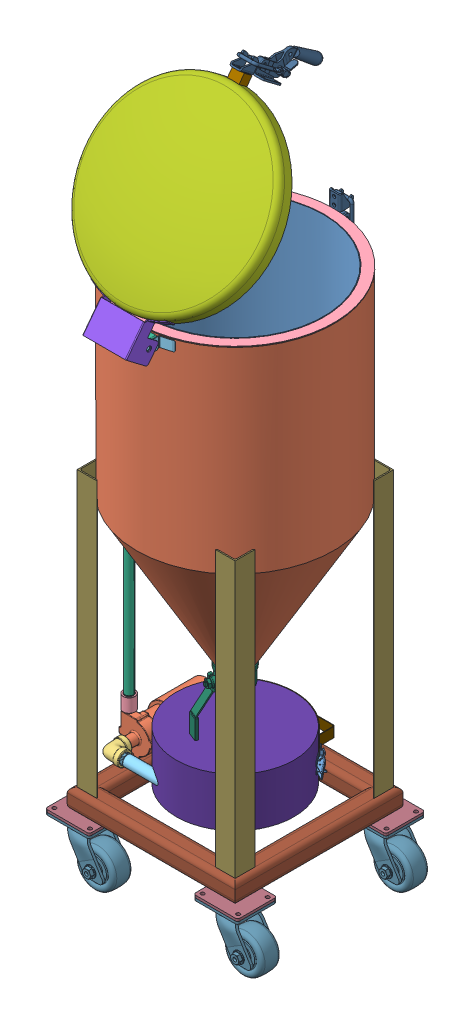
SolidWorks assembly Full Assembly - Working Copy, configuration Default. Lengths in mm.
Overall size (805.82 1990.16 905.72).
42 component instances, 28 part files, 51 mates.
Components (placement in the parent):
- Inner Tank (SUS304 Stainless)-1: Inner Tank (SUS304 Stainless) [Default] at origin size (460.38 809.15 460.38)
- Outer Tank (5052 Aluminum)-1: Outer Tank (5052 Aluminum) [Default] at (0 -53.975 0) size (510.43 880.41 510.43)
- Part2^Full Assembly - Working Copy-1: Part2^Full Assembly - Working Copy [Default] at origin size (510.43 1.27 510.43) (virtual)
- Part1^Full Assembly - Working Copy-1: Part1^Full Assembly - Working Copy [Default] at origin size (511.18 1.59 511.18) (virtual)
- Aluminum Hinge Bottom-1: Aluminum Hinge Bottom [Default] at (0 423.092 293.37) size (172.01 30.25 52.98)
- Aluminum Hinge Top-1: Aluminum Hinge Top [Default] at (0 452.7347 293.37) x (-1 0 0) z (0 0 1) size (104.78 30.94 44.15)
- Lid Assembly-1: Lid Assembly [Default] at (0 671.8933 125.664) x (-1 0 0) z (0 0.79683 -0.604203) size (548.2 438.64 642.51)
  - Lid-2: Lid [Default] at (211.2181 -60.2546 -11.3558) x (0.978448 -0.106422 -0.176957) z (0.118934 -0.410093 0.904256) size (467.18 231.16 437.78)
  - Stainless Hinge (Lid)-1: Stainless Hinge (Lid) [Default] at (0 31.628 -311.3405) x (-1 0 0) z (0 0 -1) size (198.67 69.73 99.8)
  - Part1-1: Part1 [Default] at origin size (30.23 25.4 22.84)
  - 5071A590-1: 5071A590 [Default] at (0.0381 -49.8475 255.0668) x (-1 0 0) z (0 1 0) size (60.86 76.1 227.53)
- 5071A590-1: 5071A590 [Default] at (0 407.035 -255.2141) x (1 0 0) z (0 1 0) size (60.86 76.1 227.53)
- Frame Assembly-1: Frame Assembly [Default] at (0 -711.2 0) x (-1 0 0) z (0 0 1) size (805.82 911.23 805.82)
  - Copy of Base Support^Frame Assembly-1: Copy of Base Support^Frame Assembly [Default<As Machined>] at origin size (434.34 50.8 434.34) (virtual)
  - Copy of Legs^Frame Assembly-1: Copy of Legs^Frame Assembly [Default<As Machined>] at (3.4616 1288.0635 -34.29) x (-0.788011 0 0.615661) z (0.615661 0 0.788011) size (574.08 711.2 574.08) (virtual)
  - Caster Plate-1: Caster Plate [Default] at (191.77 57.15 191.77) x (-1 0 0) z (0 0 1) size (114.3 6.35 101.6)
  - Caster Plate-2: Caster Plate [Default] at (191.77 57.15 -191.77) x (-1 0 0) z (0 0 1) size (114.3 6.35 101.6)
  - Caster Plate-3: Caster Plate [Default] at (-191.77 57.15 191.77) x (-1 0 0) z (0 0 1) size (114.3 6.35 101.6)
  - Caster Plate-4: Caster Plate [Default] at (-191.77 57.15 -191.77) x (-1 0 0) z (0 0 1) size (114.3 6.35 101.6)
  - Caster Wheels-2: Caster Wheels [2531T25] at (-236.22 149.225 191.77) x (1 0 0) z (0 0 -1) size (152.4 142.88 101.6)
  - Caster Wheels-3: Caster Wheels [2531T25] at (147.32 149.225 191.77) x (1 0 0) z (0 0 -1) size (152.4 142.88 101.6)
  - Caster Wheels-4: Caster Wheels [2531T25] at (-236.22 149.225 -191.77) x (1 0 0) z (0 0 -1) size (152.4 142.88 101.6)
  - Caster Wheels-5: Caster Wheels [2531T25] at (147.32 149.225 -191.77) x (1 0 0) z (0 0 -1) size (152.4 142.88 101.6)
- 2in Ball Valve-1: 2in Ball Valve [4286K29] at (0 -463.2428 0) x (-0.932381 0 -0.361477) z (0 1 0) size (85.6 128.78 218.48)
- Threaded Adaper - 2in-1: Threaded Adaper - 2in [Default] at (0 -351.9527 0) x (-0.837169 0 -0.546944) z (-0.546944 0 0.837169) size (63.5 76.2 63.5)
- Filter Assembly-1: Filter Assembly [Default] at (0 -638.0329 0) x (-1 0 0) z (0 0 -1) size (336.71 203.2 333.38)
  - Filter Case-1: Filter Case [Default] at origin size (304.8 127 304.8)
  - Filter Cover Plate-1: Filter Cover Plate [Default] x (-1 0 0) z (0 0 -1) size (208.06 127 68.61)
  - Threaded Adaper - 2in-2: Threaded Adaper - 2in [Default] at (0 63.5 0) size (63.5 76.2 63.5)
  - Filter Screen Latches - 1889A430-1: Filter Screen Latches - 1889A430 [Default] at (116.2139 0 99.0468) x (0 -1 0) z (-0.600065 0 0.799951) size (30 20.98 87.72)
  - Filter Screen Latches - 1889A430-2: Filter Screen Latches - 1889A430 [Default] at (-116.1817 0 98.9703) x (0 1 0) z (0.606538 0 0.795055) size (30 20.98 87.72)
- Chugger Pump-1: Chugger Pump [Default] at (-191.77 -663.956 66.675) size (88.39 112.27 235.08)
- 0.75 NPT Elbow Fitting-1: 0.75 NPT Elbow Fitting [4464K15] at (-191.77 -663.956 126.619) x (0 0 1) z (0 1 0) size (52.8 52.55 37.59)
- 0.5 NPT Coupler - 4452K114-1: 0.5 NPT Coupler - 4452K114 [4452K114] at (-217.17 -597.916 57.15) x (-0.998705 0 0.05088) z (0 1 0) size (30.48 30.48 35.05)
- 0.75 x 8 inch pipe 4548K199-1: 0.75 x 8 inch pipe 4548K199 [4548K199] at (-69.9262 -663.956 126.619) size (203.39 27.53 27.76)
- 0.5 x 18 inch pipe-1: 0.5 x 18 inch pipe [4816K124] at (-217.17 -370.332 57.15) x (0 -1 0) z (0.309099 0 -0.95103) size (458.16 22.05 22.45)
- 0.5 45 Elbow 4452K424-1: 0.5 45 Elbow 4452K424 [4452K424] at (-217.17 -161.5821 57.15) x (0 0 1) z (-1 0 0) size (30.73 48.78 41.55)
- 0.5 x 3 inch pipe-1: 0.5 x 3 inch pipe [4548K175] at (-245.3796 -111.2745 57.15) x (0.707107 -0.707107 0) z (0.690919 0.690919 0.212746) size (76.37 22.35 22.37)
- 0.5 45 Elbow 4452K424-2: 0.5 45 Elbow 4452K424 [4452K424] at (-257.9635 -98.6906 57.15) x (0 0 -1) z (0.707107 0.707107 0) size (30.73 48.78 41.55)
- 0.5 x 18 inch pipe-2: 0.5 x 18 inch pipe [4816K124] at (-273.5891 147.7829 57.15) x (0 -1 0) z (0.915986 0 0.40121) size (458.16 22.05 22.45)
- 0.5 90 Elbow 4452K424-1: 0.5 90 Elbow 4452K424 [4452K414] at (-273.5891 384.9808 57.15) x (-1 0 0) z (0 0 1) size (44.42 44.16 30.73)
- 0.5 x 2 inch pipe-1: 0.5 x 2 inch pipe [4548K173] at (-240.0448 384.9808 57.15) size (50.97 22.35 22.37)
Mates (geometry in assembly coordinates):
- Distance1: distance = 3.175 mm aligned: plane of Inner Tank (SUS304 Stainless)-1 through (0 457.2 0) normal (0 1 0); plane of Outer Tank (5052 Aluminum)-1 through (0 454.025 0) normal (0 1 0)
- Parallel2: parallel anti-aligned: plane of Aluminum Hinge Bottom-1 through (0 423.092 293.37) normal (0 1 0); plane of Aluminum Hinge Top-1 through (0 452.7347 293.37) normal (0 -1 0)
- Coincident3: coincident anti-aligned: plane of Aluminum Hinge Bottom-1 through (0 423.092 293.37) normal (1 0 0); plane of Aluminum Hinge Top-1
- Coincident4: coincident aligned: plane of Aluminum Hinge Bottom-1 through (0 421.8016 293.37) normal (0 0 1); plane of Aluminum Hinge Top-1 through (0 454.025 293.37) normal (0 0 1)
- Coincident5: coincident anti-aligned: plane of Aluminum Hinge Bottom-1 through (0 423.092 293.37) normal (0 1 0); plane of Aluminum Hinge Top-1 through (52.3875 423.092 293.37) normal (0 -1 0)
- Coincident6: coincident aligned: plane of Outer Tank (5052 Aluminum)-1 through (0 454.025 0) normal (0 1 0); plane of Aluminum Hinge Top-1 through (0 454.025 293.37) normal (0 1 0)
- Concentric3: concentric aligned: cylinder of Aluminum Hinge Top-1 through (-52.3908 437.824 279.0825) axis (1 0 0) radius 6.35; cylinder of Lid Assembly-1/Stainless Hinge (Lid)-1 through (-99.3063 437.824 279.0825) axis (1 0 0) radius 6.35
- Width1: width anti-aligned: plane of Lid Assembly-1/Stainless Hinge (Lid)-1 through (56.4832 475.2003 381.5539) normal (1 0 0); plane of Lid Assembly-1/Stainless Hinge (Lid)-1 through (-56.4832 475.2003 381.5539) normal (-1 0 0); plane of Aluminum Hinge Bottom-1 through (-53.975 369.5033 293.37) normal (-1 0 0); plane of Aluminum Hinge Bottom-1 through (53.975 369.5033 293.37) normal (1 0 0)
- Coincident7: coincident anti-aligned: plane of Part2^Full Assembly - Working Copy-1 through (0 455.295 0) normal (0 1 0); plane of 5071A590-1 through (0 455.295 -256.0523) normal (0 -1 0)
- Tangent1: tangent anti-aligned: cylinder of Outer Tank (5052 Aluminum)-1 through (0 454.025 0) axis (0 -1 0) radius 255.2141; plane of 5071A590-1 through (-26.924 437.261 -255.2141) normal (0 0 1)
- Coincident8: coincident: plane of 5071A590-1; point of assembly
- Distance2: distance = 711.2 mm anti-aligned: plane of assembly through (0 0 0) normal (0 1 0); plane of Frame Assembly-1/Copy of Base Support^Frame Assembly-1
- Coincident10: coincident aligned: plane of Frame Assembly-1/Copy of Base Support^Frame Assembly-1 through (0 -711.2 0) normal (0 0 1); plane of assembly through (0 0 0) normal (0 0 1)
- Coincident11: coincident anti-aligned: plane of Frame Assembly-1/Copy of Base Support^Frame Assembly-1; plane of assembly through (0 0 0) normal (1 0 0)
- Coincident12: coincident aligned: plane of 5071A590-1; plane of assembly through (0 0 0) normal (1 0 0)
- Coincident13: coincident aligned: plane of Aluminum Hinge Bottom-1 through (0 423.092 293.37) normal (1 0 0); plane of 5071A590-1
- Concentric4: concentric aligned: cylinder of Inner Tank (SUS304 Stainless)-1 through (0 457.2 0) axis (0 -1 0) radius 228.6; cylinder of Outer Tank (5052 Aluminum)-1 through (0 454.025 0) axis (0 -1 0) radius 254
- Distance3: distance = 293.37 mm aligned: plane of assembly through (0 0 0) normal (0 0 1); plane of Aluminum Hinge Bottom-1 through (0 423.092 293.37) normal (0 0 1)
- Coincident15: coincident anti-aligned: plane of Inner Tank (SUS304 Stainless)-1 through (25.4 -351.9527 0) normal (0 -1 0); plane of Threaded Adaper - 2in-1 through (0 -351.9527 0) normal (0 1 0)
- Concentric5: concentric aligned: circle of Inner Tank (SUS304 Stainless)-1; cylinder of Threaded Adaper - 2in-1 through (0 -428.1527 0) axis (0 1 0) radius 19.05
- Concentric6: concentric aligned: cylinder of 2in Ball Valve-1 through (0 -497.2407 0) axis (0 1 0) radius 24.9936; cylinder of Threaded Adaper - 2in-1 through (0 -428.1527 0) axis (0 1 0) radius 19.05
- Coincident16: coincident anti-aligned: plane of 2in Ball Valve-1 through (-14.2914 -402.7527 36.8626) normal (0 1 0); plane of Threaded Adaper - 2in-1 through (0 -402.7527 0) normal (0 -1 0)
- Concentric7: concentric anti-aligned: cylinder of 2in Ball Valve-1 through (0 -497.2407 0) axis (0 1 0) radius 24.9936; cylinder of Filter Assembly-1/Threaded Adaper - 2in-2 through (0 -498.3329 0) axis (0 -1 0) radius 31.75
- Coincident17: coincident aligned: circle of 2in Ball Valve-1; plane of Filter Assembly-1/Threaded Adaper - 2in-2 through (0 -523.7329 0) normal (0 1 0)
- Coincident18: coincident anti-aligned: plane of Filter Assembly-1/Filter Case-1 through (0 -638.0329 0) normal (-1 0 0); plane of assembly through (0 0 0) normal (1 0 0)
- Coincident19: coincident anti-aligned: plane of Frame Assembly-1/Copy of Base Support^Frame Assembly-1 through (-179.07 -711.2 204.47) normal (0 1 0); plane of Chugger Pump-1 through (-235.966 -711.2 -101.981) normal (0 -1 0)
- Width4: width anti-aligned: plane of Chugger Pump-1 through (-235.966 -709.93 -101.981) normal (-1 0 0); plane of Chugger Pump-1 through (-147.574 -709.93 -101.981) normal (1 0 0); plane of Frame Assembly-1/Copy of Base Support^Frame Assembly-1 through (-166.37 -723.9 204.47) normal (1 0 0); plane of Frame Assembly-1/Copy of Base Support^Frame Assembly-1 through (-217.17 -749.3 204.47) normal (-1 0 0)
- Concentric9: concentric anti-aligned: cylinder of Chugger Pump-1 through (-217.17 -598.932 57.15) axis (0 1 0) radius 8.412; cylinder of 0.5 NPT Coupler - 4452K114-1 through (-217.17 -580.39 57.15) axis (0 -1 0) radius 15.24
- Coincident23: coincident anti-aligned: plane of Chugger Pump-1 through (-227.33 -615.442 57.15) normal (0 1 0); plane of 0.5 NPT Coupler - 4452K114-1 through (-217.17 -615.442 57.15) normal (0 -1 0)
- Concentric10: concentric anti-aligned: cylinder of Chugger Pump-1 through (-191.77 -663.956 109.855) axis (0 0 -1) radius 12.954; cylinder of 0.75 NPT Elbow Fitting-1 through (-191.77 -663.956 93.345) axis (0 0 1) radius 18.796
- Coincident24: coincident anti-aligned: plane of Chugger Pump-1 through (-191.77 -652.526 93.345) normal (0 0 1); plane of 0.75 NPT Elbow Fitting-1 through (-191.77 -663.956 93.345) normal (0 0 -1)
- Parallel5: parallel aligned: plane of 0.75 NPT Elbow Fitting-1 through (-191.77 -663.956 126.619) normal (0 1 0); plane of assembly through (0 0 0) normal (0 1 0)
- Concentric11: concentric anti-aligned: cylinder of 0.75 NPT Elbow Fitting-1 through (-158.496 -663.956 126.619) axis (-1 0 0) radius 18.796; cylinder of 0.75 x 8 inch pipe 4548K199-1 through (-69.9262 -663.956 126.619) axis (1 0 0) radius 13.335
- Coincident26: coincident aligned: plane of 0.75 NPT Elbow Fitting-1 through (-171.5262 -663.956 126.619) normal (-1 0 0); plane of 0.75 x 8 inch pipe 4548K199-1 through (-171.5262 -663.956 126.619) normal (-1 0 0)
- Concentric13: concentric anti-aligned: cylinder of 0.5 NPT Coupler - 4452K114-1 through (-217.17 -580.39 57.15) axis (0 -1 0) radius 15.24; cylinder of 0.5 x 18 inch pipe-1 through (-217.17 -598.932 57.15) axis (0 1 0) radius 10.668
- Coincident28: coincident anti-aligned: circle of Chugger Pump-1; plane of 0.5 x 18 inch pipe-1 through (-217.17 -598.932 57.15) normal (0 -1 0)
- Concentric14: concentric anti-aligned: cylinder of 0.5 x 18 inch pipe-1 through (-217.17 -598.932 57.15) axis (0 1 0) radius 10.668; cylinder of 0.5 45 Elbow 4452K424-1 through (-217.17 -152.7429 57.15) axis (0 -1 0) radius 15.367
- Distance5: distance = 57.15 mm aligned: plane of 0.5 45 Elbow 4452K424-1 through (-217.17 -161.5821 57.15) normal (0 0 1); plane of assembly through (0 0 0) normal (0 0 1)
- Concentric15: concentric anti-aligned: cylinder of 0.5 45 Elbow 4452K424-1 through (-226.5454 -130.1087 57.15) axis (-0.707107 0.707107 0) radius 15.367; cylinder of 0.5 x 3 inch pipe-1 through (-245.3796 -111.2745 57.15) axis (0.707107 -0.707107 0) radius 10.668
- Coincident30: coincident aligned: circle of 0.5 x 18 inch pipe-1; plane of 0.5 45 Elbow 4452K424-1 through (-217.17 -161.5821 57.15) normal (0 -1 0)
- Coincident31: coincident anti-aligned: plane of 0.5 45 Elbow 4452K424-1 through (-232.7956 -123.8585 57.15) normal (-0.707107 0.707107 0); circle of 0.5 x 3 inch pipe-1
- Concentric16: concentric anti-aligned: cylinder of 0.5 45 Elbow 4452K424-1 through (-226.5454 -130.1087 57.15) axis (-0.707107 0.707107 0) radius 15.367; cylinder of 0.5 45 Elbow 4452K424-2 through (-264.2137 -92.4404 57.15) axis (0.707107 -0.707107 0) radius 15.367
- Parallel7: parallel anti-aligned: plane of 0.5 45 Elbow 4452K424-2; plane of assembly through (0 0 0) normal (0 0 1)
- Coincident33: coincident aligned: circle of 0.5 x 3 inch pipe-1; plane of 0.5 45 Elbow 4452K424-2 through (-257.9635 -98.6906 57.15) normal (0.707107 -0.707107 0)
- Concentric17: concentric aligned: cylinder of 0.5 45 Elbow 4452K424-2 through (-273.5891 -69.8062 57.15) axis (0 1 0) radius 15.367; cylinder of 0.5 x 18 inch pipe-2 through (-273.5891 -80.8171 57.15) axis (0 1 0) radius 10.668
- Coincident35: coincident aligned: plane of 0.5 45 Elbow 4452K424-2 through (-273.5891 -60.967 57.15) normal (0 1 0); circle of 0.5 x 18 inch pipe-2
- Concentric18: concentric aligned: cylinder of 0.5 x 18 inch pipe-2 through (-273.5891 -80.8171 57.15) axis (0 1 0) radius 10.668; cylinder of 0.5 90 Elbow 4452K424-1 through (-273.5891 356.5328 57.15) axis (0 1 0) radius 15.367
- Coincident36: coincident aligned: circle of 0.5 x 18 inch pipe-2; plane of 0.5 90 Elbow 4452K424-1 through (-273.5891 356.5328 57.15) normal (0 -1 0)
- Parallel8: parallel aligned: plane of 0.5 90 Elbow 4452K424-1 through (-273.5891 384.9808 57.15) normal (0 0 1); plane of assembly through (0 0 0) normal (0 0 1)
- Concentric19: concentric anti-aligned: cylinder of 0.5 90 Elbow 4452K424-1 through (-245.1411 384.9808 57.15) axis (-1 0 0) radius 15.367; cylinder of 0.5 x 2 inch pipe-1 through (-240.0448 384.9808 57.15) axis (1 0 0) radius 10.668
- Coincident37: coincident aligned: plane of 0.5 90 Elbow 4452K424-1 through (-245.1411 384.9808 57.15) normal (1 0 0); circle of 0.5 x 2 inch pipe-1
